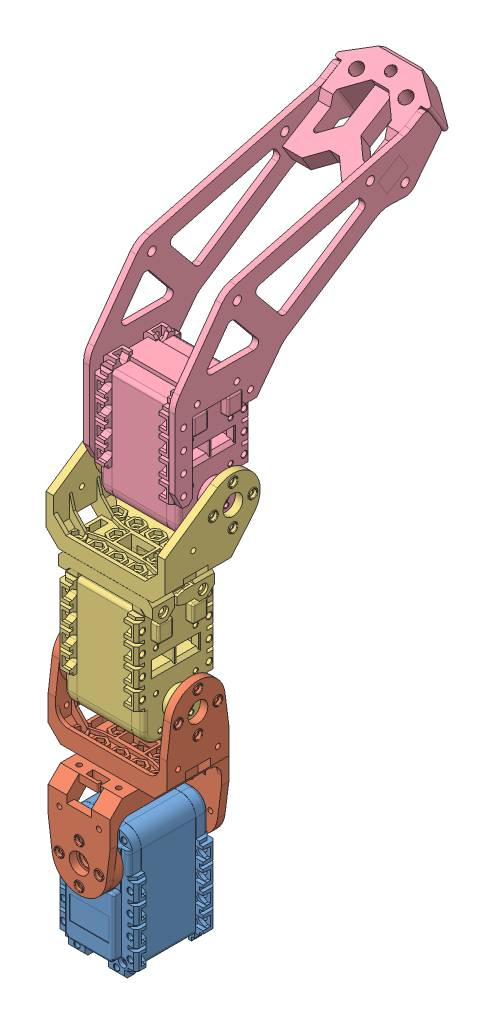
SolidWorks assembly Right_Leg_with_Servo, configuration Default. Lengths in mm.
Overall size (49.4 253.44 138.92).
4 component instances, 4 part files, 9 mates.
Components (placement in the parent):
- ServoBody-1: ServoBody [Default] at (1.7715 35.525 50.0961) size (32 50.04 38.67)
- Coxa_right-1: Coxa_right [Default] at (6.8332 73.9514 95.002) x (1 0 0) z (0 0 -1) size (48.5 75 48.5)
- Femur_right-1: Femur_right [Default] at (38.3398 114.3313 34.2621) x (0 0 1) z (-1 0 0) size (42.04 87.04 48.5)
- Tibia_right-1: Tibia_right [Default] at (-48.0745 133.3986 22.0282) x (0 0 1) z (1 0 0) size (116.62 108.98 38.67)
Mates (geometry in assembly coordinates):
- Concentric4: concentric anti-aligned: cylinder of ServoBody-1 through (1.7715 35.525 63.4961) axis (0 0 1) radius 4.6; cone of Coxa_right-1 through (1.7715 35.525 66.3561) axis (0 0 -1)
- Coincident7: coincident anti-aligned: plane of ServoBody-1 through (-3.0125 30.741 63.4961) normal (0 0 1); plane of Coxa_right-1 through (-2.4019 31.3559 63.4961) normal (0 0 -1)
- Parallel4: parallel aligned: plane of ServoBody-1 through (-11.2285 41.815 35.0161) normal (-1 0 0); plane of Coxa_right-1 through (-10.7285 62.025 25.1961) normal (-1 0 0)
- Concentric5: concentric anti-aligned: cone of Coxa_right-1 through (-15.3888 88.525 49.1964) axis (1 0 0); cylinder of Femur_right-1 through (-12.5288 88.525 49.1964) axis (-1 0 0) radius 4.6
- Coincident8: coincident anti-aligned: plane of Coxa_right-1 through (-12.5288 92.6941 53.3699) normal (1 0 0); plane of Femur_right-1 through (-12.5288 93.309 53.9804) normal (-1 0 0)
- Parallel5: parallel anti-aligned: plane of Coxa_right-1 through (-14.2288 69.025 61.6972) normal (0 1 0); plane of Femur_right-1 through (15.9592 77.025 41.9164) normal (0 -1 0)
- Concentric6: concentric: cone of Femur_right-1 through (-16.2885 153.025 34.1538) axis (1 0 0); cylinder of Tibia_right-1 through (246.4827 153.025 34.1538) axis (-1 0 0) radius 4.6
- Coincident11: coincident anti-aligned: plane of Femur_right-1 through (-13.4285 157.1941 38.3273) normal (1 0 0); plane of Tibia_right-1 through (-13.4285 157.809 38.9378) normal (-1 0 0)
- Parallel6: parallel: plane of Femur_right-1 through (-15.1285 136.025 64.1538) normal (0 1 0); plane of Tibia_right-1 through (15.0595 141.525 26.8738) normal (0 -1 0)
